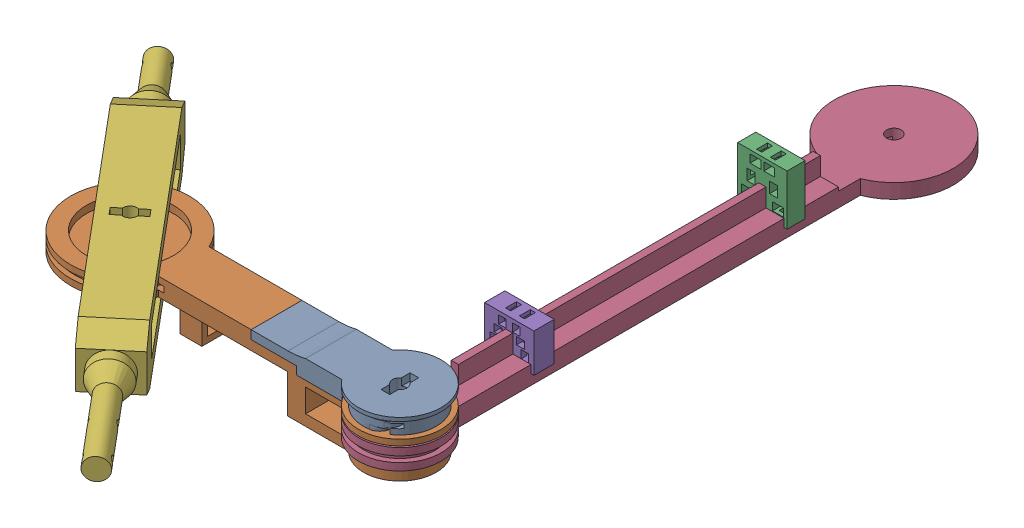
SolidWorks assembly MainAssembly, configuration Default. Lengths in mm.
Overall size (68.49 10.2 107.47).
3 component instances, 3 part files, 6 mates.
Components (placement in the parent):
- Humerus_V1_Main-1: Humerus_V1_Main [Default] at (652.4425 871.97 1286.6467) size (51.1 8.1 16.4)
- Radius_V1_Main-1: Radius_V1_Main [Default] at (689.6425 869.17 1286.6467) size (16.4 8.5 82)
- ShoulderBracket_V1-1: ShoulderBracket_V1 [Default] at (663.4206 872.37 1305.1749) x (-0.642788 0 -0.766044) z (0.766044 0 -0.642788) size (69.5 8.2 7)
Mates (geometry in assembly coordinates):
- Concentric1: concentric: cylinder of Humerus_V1_Main-1 through (689.6425 871.47 1286.6467) axis (0 1 0) radius 1; cylinder of Radius_V1_Main-1 through (689.6425 868.17 1286.6467) axis (0 1 0) radius 1.925
- Distance1: distance = 0.2 mm: plane of Radius_V1_Main-1 through (689.6425 870.97 1286.6467) normal (0 1 0); plane of Humerus_V1_Main-1 through (689.6425 871.17 1286.6467) normal (0 -1 0)
- Concentric2: concentric aligned: cylinder of Humerus_V1_Main-1 through (652.4425 866.1131 1286.6467) axis (0 1 0) radius 2; cylinder of ShoulderBracket_V1-1 through (652.4425 871.6416 1286.6467) axis (0 1 0) radius 1
- Distance2: distance = 0.2 mm anti-aligned: plane of Humerus_V1_Main-1 through (652.4425 874.27 1286.6467) normal (0 1 0); plane of ShoulderBracket_V1-1 through (665.5689 874.47 1296.8452) normal (0 -1 0)
- Angle1: planar angle = 0.872665 rad aligned: plane of ShoulderBracket_V1-1 through (663.4206 872.37 1305.1749) normal (-0.766044 0 0.642788); plane of Humerus_V1_Main-1 through (-399310.3575 874.27 1290.1467) normal (0 0 1)
- Angle2: planar angle = 1.570796 rad anti-aligned: plane of Radius_V1_Main-1 through (686.6425 870.82 1286.6467) normal (-1 0 0); plane of Humerus_V1_Main-1 through (-399310.3575 874.27 1283.1467) normal (0 0 -1)
